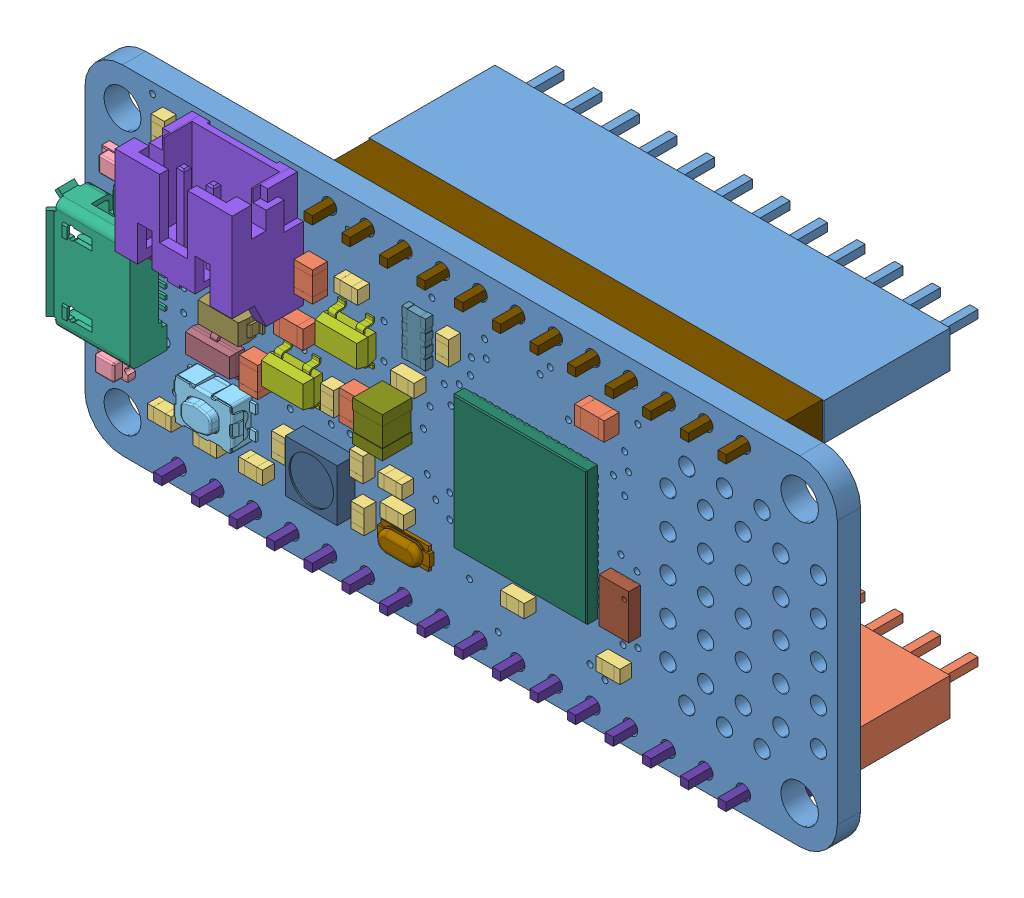
SolidWorks assembly 3857 Adafruit Feather M4 Express headers 2, configuration Default. Lengths in mm.
Overall size (50.85 22.86 20.37).
43 component instances, 20 part files, 13 mates.
Components (placement in the parent):
- 3857 Adafruit Feather M4 Express-1: 3857 Adafruit Feather M4 Express [Default] at origin size (50.85 22.86 6.37)
  - 3857 Adafruit Feather M4 Express(2)^3857 Adafruit Feather M4 Express-1: 3857 Adafruit Feather M4 Express(2)^3857 Adafruit Feather M4 Express [Default] at origin size (50.85 22.86 6.37) (virtual)
    - PCB Component^3857 Adafruit Feather M4 Express(2)_3857 Adafruit Feather M4 Express-1: PCB Component^3857 Adafruit Feather M4 Express(2)_3857 Adafruit Feather M4 Express [Default] at origin size (50.85 22.86 6.37) (virtual)
      - Board^PCB Component_3857 Adafruit Feather M4 Express(2)_3857 Adafruit Feather M4 Express-1: Board^PCB Component_3857 Adafruit Feather M4 Express(2)_3857 Adafruit Feather M4 Express [Default] at origin size (50.8 22.86 1.57) (virtual)
      - 10uF^PCB Component_3857 Adafruit Feather M4 Express(2)_3857 Adafruit Feather M4 Express-1: 10uF^PCB Component_3857 Adafruit Feather M4 Express(2)_3857 Adafruit Feather M4 Express [Default] at (12.042 9.838 1.57) x (0 -1 0) z (0 0 1) size (2 1.25 1) (virtual)
      - 10uF^PCB Component_3857 Adafruit Feather M4 Express(2)_3857 Adafruit Feather M4 Express-2: 10uF^PCB Component_3857 Adafruit Feather M4 Express(2)_3857 Adafruit Feather M4 Express [Default] at (14.728 13.858 1.57) size (2 1.25 1) (virtual)
      - 10uF^PCB Component_3857 Adafruit Feather M4 Express(2)_3857 Adafruit Feather M4 Express-3: 10uF^PCB Component_3857 Adafruit Feather M4 Express(2)_3857 Adafruit Feather M4 Express [Default] at (15.748 17.272 1.57) x (0 -1 0) z (0 0 1) size (2 1.25 1) (virtual)
      - 10uF^PCB Component_3857 Adafruit Feather M4 Express(2)_3857 Adafruit Feather M4 Express-4: 10uF^PCB Component_3857 Adafruit Feather M4 Express(2)_3857 Adafruit Feather M4 Express [Default] at (35.065 18.669 1.57) size (2 1.25 1) (virtual)
      - 10uF^PCB Component_3857 Adafruit Feather M4 Express(2)_3857 Adafruit Feather M4 Express-5: 10uF^PCB Component_3857 Adafruit Feather M4 Express(2)_3857 Adafruit Feather M4 Express [Default] at (18.796 11.303 1.57) x (0 -1 0) z (0 0 1) size (2 1.25 1) (virtual)
      - 1uF^PCB Component_3857 Adafruit Feather M4 Express(2)_3857 Adafruit Feather M4 Express-1: 1uF^PCB Component_3857 Adafruit Feather M4 Express(2)_3857 Adafruit Feather M4 Express [Default] at (24.909 17.78 1.57) x (0 1 0) z (0 0 1) size (1.6 0.9 0.8) (virtual)
      - 1uF^PCB Component_3857 Adafruit Feather M4 Express(2)_3857 Adafruit Feather M4 Express-2: 1uF^PCB Component_3857 Adafruit Feather M4 Express(2)_3857 Adafruit Feather M4 Express [Default] at (11.989 4.218 1.57) size (1.6 0.9 0.8) (virtual)
      - 1uF^PCB Component_3857 Adafruit Feather M4 Express(2)_3857 Adafruit Feather M4 Express-3: 1uF^PCB Component_3857 Adafruit Feather M4 Express(2)_3857 Adafruit Feather M4 Express [Default] at (5.715 20.955 1.57) x (0 -1 0) z (0 0 1) size (1.6 0.9 0.8) (virtual)
      - 1uF^PCB Component_3857 Adafruit Feather M4 Express(2)_3857 Adafruit Feather M4 Express-4: 1uF^PCB Component_3857 Adafruit Feather M4 Express(2)_3857 Adafruit Feather M4 Express [Default] at (5.829 4.254 1.57) size (1.6 0.9 0.8) (virtual)
      - 1uF^PCB Component_3857 Adafruit Feather M4 Express(2)_3857 Adafruit Feather M4 Express-5: 1uF^PCB Component_3857 Adafruit Feather M4 Express(2)_3857 Adafruit Feather M4 Express [Default] at (18.415 17.97 1.57) size (1.6 0.9 0.8) (virtual)
      - 1uF^PCB Component_3857 Adafruit Feather M4 Express(2)_3857 Adafruit Feather M4 Express-6: 1uF^PCB Component_3857 Adafruit Feather M4 Express(2)_3857 Adafruit Feather M4 Express [Default] at (19.202 5.067 1.57) x (0 1 0) z (0 0 1) size (1.6 0.9 0.8) (virtual)
      - 1uF^PCB Component_3857 Adafruit Feather M4 Express(2)_3857 Adafruit Feather M4 Express-7: 1uF^PCB Component_3857 Adafruit Feather M4 Express(2)_3857 Adafruit Feather M4 Express [Default] at (21.526 6.35 1.57) x (-1 0 0) z (0 0 1) size (1.6 0.9 0.8) (virtual)
      - 1uF^PCB Component_3857 Adafruit Feather M4 Express(2)_3857 Adafruit Feather M4 Express-8: 1uF^PCB Component_3857 Adafruit Feather M4 Express(2)_3857 Adafruit Feather M4 Express [Default] at (36.119 4.648 1.57) x (-1 0 0) z (0 0 1) size (1.6 0.9 0.8) (virtual)
      - 1uF^PCB Component_3857 Adafruit Feather M4 Express(2)_3857 Adafruit Feather M4 Express-9: 1uF^PCB Component_3857 Adafruit Feather M4 Express(2)_3857 Adafruit Feather M4 Express [Default] at (19.126 8.065 1.57) x (0 1 0) z (0 0 1) size (1.6 0.9 0.8) (virtual)
      - 1uF^PCB Component_3857 Adafruit Feather M4 Express(2)_3857 Adafruit Feather M4 Express-10: 1uF^PCB Component_3857 Adafruit Feather M4 Express(2)_3857 Adafruit Feather M4 Express [Default] at (29.662 5.263 1.57) x (-1 0 0) z (0 0 1) size (1.6 0.9 0.8) (virtual)
      - 1uF^PCB Component_3857 Adafruit Feather M4 Express(2)_3857 Adafruit Feather M4 Express-11: 1uF^PCB Component_3857 Adafruit Feather M4 Express(2)_3857 Adafruit Feather M4 Express [Default] at (8.89 4.254 1.57) x (-1 0 0) z (0 0 1) size (1.6 0.9 0.8) (virtual)
      - 1uF^PCB Component_3857 Adafruit Feather M4 Express(2)_3857 Adafruit Feather M4 Express-12: 1uF^PCB Component_3857 Adafruit Feather M4 Express(2)_3857 Adafruit Feather M4 Express [Default] at (17.145 10.922 1.57) x (0 1 0) z (0 0 1) size (1.6 0.9 0.8) (virtual)
      - 1uF^PCB Component_3857 Adafruit Feather M4 Express(2)_3857 Adafruit Feather M4 Express-13: 1uF^PCB Component_3857 Adafruit Feather M4 Express(2)_3857 Adafruit Feather M4 Express [Default] at (13.856 6.502 1.57) x (0 -1 0) z (0 0 1) size (1.6 0.9 0.8) (virtual)
      - 1uF^PCB Component_3857 Adafruit Feather M4 Express(2)_3857 Adafruit Feather M4 Express-14: 1uF^PCB Component_3857 Adafruit Feather M4 Express(2)_3857 Adafruit Feather M4 Express [Default] at (21.4 8.065 1.57) size (1.6 0.9 0.8) (virtual)
      - 1uF^PCB Component_3857 Adafruit Feather M4 Express(2)_3857 Adafruit Feather M4 Express-15: 1uF^PCB Component_3857 Adafruit Feather M4 Express(2)_3857 Adafruit Feather M4 Express [Default] at (22.225 14.414 1.57) x (-1 0 0) z (0 0 1) size (1.6 0.9 0.8) (virtual)
      - ORANGE^PCB Component_3857 Adafruit Feather M4 Express(2)_3857 Adafruit Feather M4 Express-1: ORANGE^PCB Component_3857 Adafruit Feather M4 Express(2)_3857 Adafruit Feather M4 Express [Default] at (2.645 17.359 1.57) x (0 1 0) z (0 0 1) size (1.25 2.02 1.1) (virtual)
      - ORANGE^PCB Component_3857 Adafruit Feather M4 Express(2)_3857 Adafruit Feather M4 Express-2: ORANGE^PCB Component_3857 Adafruit Feather M4 Express(2)_3857 Adafruit Feather M4 Express [Default] at (2.413 5.588 1.57) x (0 -1 0) z (0 0 1) size (1.25 2.02 1.1) (virtual)
      - KMR2^PCB Component_3857 Adafruit Feather M4 Express(2)_3857 Adafruit Feather M4 Express-1: KMR2^PCB Component_3857 Adafruit Feather M4 Express(2)_3857 Adafruit Feather M4 Express [Default] at (9.398 6.54 1.57) x (-1 0 0) z (0 0 1) size (4.6 2.8 1.94) (virtual)
      - microUSB^PCB Component_3857 Adafruit Feather M4 Express(2)_3857 Adafruit Feather M4 Express-1: microUSB^PCB Component_3857 Adafruit Feather M4 Express(2)_3857 Adafruit Feather M4 Express [Default] at (4.445 11.43 1.57) x (0 -1 0) z (0 0 1) size (8.8 5.6 3) (virtual)
      - MCP73831T-2ACI_OT^PCB Component_3857 Adafruit Feather M4 Express(2)_3857 Adafruit Feather M4 Express-1: MCP73831T-2ACI_OT^PCB Component_3857 Adafruit Feather M4 Express(2)_3857 Adafruit Feather M4 Express [Default] at (14.732 10.922 1.57) size (3 3 1.4) (virtual)
      - MCP73831T-2ACI_OT^PCB Component_3857 Adafruit Feather M4 Express(2)_3857 Adafruit Feather M4 Express-2: MCP73831T-2ACI_OT^PCB Component_3857 Adafruit Feather M4 Express(2)_3857 Adafruit Feather M4 Express [Default] at (18.352 15.113 1.57) size (3 3 1.4) (virtual)
      - JSTPH^PCB Component_3857 Adafruit Feather M4 Express(2)_3857 Adafruit Feather M4 Express-1: JSTPH^PCB Component_3857 Adafruit Feather M4 Express(2)_3857 Adafruit Feather M4 Express [Default] at (10.795 19.304 1.57) size (7.9 8.6 4.8) (virtual)
      - 32.768^PCB Component_3857 Adafruit Feather M4 Express(2)_3857 Adafruit Feather M4 Express-1: 32.768^PCB Component_3857 Adafruit Feather M4 Express(2)_3857 Adafruit Feather M4 Express [Default] at (21.806 4.496 1.57) x (-1 0 0) z (0 0 1) size (3.5 1.5 0.8) (virtual)
      - WS2812B3535^PCB Component_3857 Adafruit Feather M4 Express(2)_3857 Adafruit Feather M4 Express-1: WS2812B3535^PCB Component_3857 Adafruit Feather M4 Express(2)_3857 Adafruit Feather M4 Express [Default] at (16.485 6.109 1.57) x (0 -1 0) z (0 0 1) size (3.5 3.5 1.2) (virtual)
      - 2MB Flash^PCB Component_3857 Adafruit Feather M4 Express(2)_3857 Adafruit Feather M4 Express-1: 2MB Flash^PCB Component_3857 Adafruit Feather M4 Express(2)_3857 Adafruit Feather M4 Express [Default] at (36.512 8.433 1.57) x (0 1 0) z (0 0 1) size (3 2 0.8) (virtual)
      - MBR120^PCB Component_3857 Adafruit Feather M4 Express(2)_3857 Adafruit Feather M4 Express-1: MBR120^PCB Component_3857 Adafruit Feather M4 Express(2)_3857 Adafruit Feather M4 Express [Default] at (10.35 12.319 1.57) x (-1 0 0) z (0 0 1) size (3.6 1.4 1.35) (virtual)
      - DMG341^PCB Component_3857 Adafruit Feather M4 Express(2)_3857 Adafruit Feather M4 Express-1: DMG341^PCB Component_3857 Adafruit Feather M4 Express(2)_3857 Adafruit Feather M4 Express [Default] at (9.398 9.842 1.57) size (3.04 2.64 1.12) (virtual)
      - 100K^PCB Component_3857 Adafruit Feather M4 Express(2)_3857 Adafruit Feather M4 Express-1: 100K^PCB Component_3857 Adafruit Feather M4 Express(2)_3857 Adafruit Feather M4 Express [Default] at (22.67 17.208 1.57) x (0 1 0) z (0 0 1) size (3.05 1.6 0.5) (virtual)
      - ATSAMD51J^PCB Component_3857 Adafruit Feather M4 Express(2)_3857 Adafruit Feather M4 Express-1: ATSAMD51J^PCB Component_3857 Adafruit Feather M4 Express(2)_3857 Adafruit Feather M4 Express [Default] at (30.162 11.049 1.57) x (0 1 0) z (0 0 1) size (9 9 0.8) (virtual)
      - 10uH^PCB Component_3857 Adafruit Feather M4 Express(2)_3857 Adafruit Feather M4 Express-1: 10uH^PCB Component_3857 Adafruit Feather M4 Express(2)_3857 Adafruit Feather M4 Express [Default] at (21.082 11.811 1.57) x (0 -1 0) z (0 0 1) size (2.7 2 2) (virtual)
- header_m16-1: header_m16 [Default] at (5.08 1.27 -2.5) x (1 0 0) z (0 -1 0) size (40.64 11.5 2.5)
- header_m12-1: header_m12 [Default] at (15.24 21.59 -2.5) x (1 0 0) z (0 -1 0) size (30.48 11.5 2.5)
- header_f12-1: header_f12 [Default] at (15.115 21.59 -11) x (1 0 0) z (0 -1 0) size (30.73 11.5 2.5)
- header_f16-1: header_f16 [Default] at (4.955 1.27 -11) x (1 0 0) z (0 -1 0) size (40.89 11.5 2.5)
Mates (geometry in assembly coordinates):
- Concentric1: concentric anti-aligned: line of header_m12-1 through (16.51 21.59 -2.5) axis (0 0 -1); cylinder of 3857 Adafruit Feather M4 Express-1/3857 Adafruit Feather M4 Express(2)^3857 Adafruit Feather M4 Express-1/PCB Component^3857 Adafruit Feather M4 Express(2)_3857 Adafruit Feather M4 Express-1/Board^PCB Component_3857 Adafruit Feather M4 Express(2)_3857 Adafruit Feather M4 Express-1 through (16.51 21.59 0) axis (0 0 1) radius 0.5
- Concentric3: concentric anti-aligned: cylinder of 3857 Adafruit Feather M4 Express-1/3857 Adafruit Feather M4 Express(2)^3857 Adafruit Feather M4 Express-1/PCB Component^3857 Adafruit Feather M4 Express(2)_3857 Adafruit Feather M4 Express-1/Board^PCB Component_3857 Adafruit Feather M4 Express(2)_3857 Adafruit Feather M4 Express-1 through (44.45 21.59 0) axis (0 0 1) radius 0.5; line of header_m12-1 through (44.45 21.59 -2.5) axis (0 0 -1)
- Coincident1: coincident anti-aligned: plane of 3857 Adafruit Feather M4 Express-1/3857 Adafruit Feather M4 Express(2)^3857 Adafruit Feather M4 Express-1/PCB Component^3857 Adafruit Feather M4 Express(2)_3857 Adafruit Feather M4 Express-1/Board^PCB Component_3857 Adafruit Feather M4 Express(2)_3857 Adafruit Feather M4 Express-1 through (25.4 11.43 0) normal (0 0 -1); plane of header_m12-1 through (15.24 20.34 0) normal (0 0 1)
- Concentric4: concentric anti-aligned: cylinder of 3857 Adafruit Feather M4 Express-1/3857 Adafruit Feather M4 Express(2)^3857 Adafruit Feather M4 Express-1/PCB Component^3857 Adafruit Feather M4 Express(2)_3857 Adafruit Feather M4 Express-1/Board^PCB Component_3857 Adafruit Feather M4 Express(2)_3857 Adafruit Feather M4 Express-1 through (6.35 1.27 0) axis (0 0 1) radius 0.5; line of header_m16-1 through (6.35 1.27 -2.5) axis (0 0 -1)
- Concentric6: concentric anti-aligned: cylinder of 3857 Adafruit Feather M4 Express-1/3857 Adafruit Feather M4 Express(2)^3857 Adafruit Feather M4 Express-1/PCB Component^3857 Adafruit Feather M4 Express(2)_3857 Adafruit Feather M4 Express-1/Board^PCB Component_3857 Adafruit Feather M4 Express(2)_3857 Adafruit Feather M4 Express-1 through (44.45 1.27 0) axis (0 0 1) radius 0.5; line of header_m16-1 through (44.45 1.27 -2.5) axis (0 0 -1)
- Coincident4: coincident anti-aligned: plane of 3857 Adafruit Feather M4 Express-1/3857 Adafruit Feather M4 Express(2)^3857 Adafruit Feather M4 Express-1/PCB Component^3857 Adafruit Feather M4 Express(2)_3857 Adafruit Feather M4 Express-1/Board^PCB Component_3857 Adafruit Feather M4 Express(2)_3857 Adafruit Feather M4 Express-1 through (25.4 11.43 0) normal (0 0 -1); plane of header_m16-1 through (5.08 0.02 0) normal (0 0 1)
- Coincident5: coincident anti-aligned: plane of header_m12-1 through (15.24 20.34 -2.5) normal (0 0 -1); plane of header_f12-1 through (15.115 20.34 -2.5) normal (0 0 1)
- Coincident6: coincident aligned: line of header_m12-1 through (16.51 21.59 -2.5) axis (0 0 -1); line of header_f12-1 through (16.51 21.59 -11) axis (0 0 -1)
- Coincident7: coincident aligned: line of header_m12-1 through (44.45 21.59 -2.5) axis (0 0 -1); line of header_f12-1 through (44.45 21.59 -11) axis (0 0 -1)
- Coincident8: coincident anti-aligned: plane of header_m16-1 through (5.08 0.02 -2.5) normal (0 0 -1); plane of header_f12-2 through (7.0492 0.02 -2.5) normal (0 0 1)
- Coincident10: coincident anti-aligned: plane of header_m16-1 through (5.08 0.02 -2.5) normal (0 0 -1); plane of header_f16-1 through (4.955 0.02 -2.5) normal (0 0 1)
- Coincident11: coincident aligned: line of header_m16-1 through (6.35 1.27 -2.5) axis (0 0 -1); line of header_f16-1 through (6.35 1.27 -11) axis (0 0 -1)
- Coincident12: coincident aligned: line of header_m16-1 through (44.45 1.27 -2.5) axis (0 0 -1); line of header_f16-1 through (44.45 1.27 -11) axis (0 0 -1)
